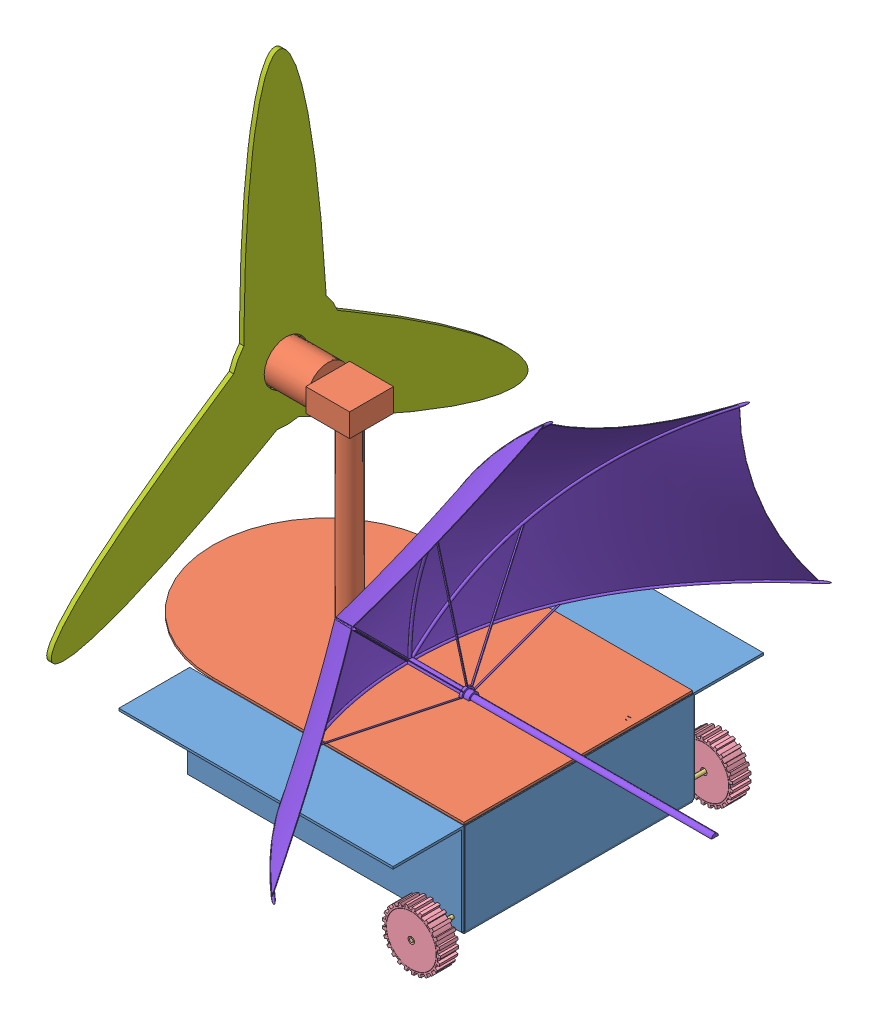
SolidWorks assembly eco_bot, configuration Default. Lengths in mm.
Overall size (551.58 654.61 611.22).
10 component instances, 8 part files, 21 mates.
Components (placement in the parent):
- eco_bot_chasssis-1: eco_bot_chasssis [Default] at (134.5678 118.3464 332.5664) size (301 102.54 405.08)
- eco_bot_upper_cover-1: eco_bot_upper_cover [Default] at (145.8453 220.8864 348.4548) x (0 0 -1) z (1 0 0) size (250 238.55 400)
- shaft_eco-1: shaft_eco [Default] at (286.9011 130.8864 513.8635) x (0 0 -1) z (1 0 0) size (340 4 4)
- wheel_eco-1: wheel_eco [Default] at (286.9011 130.8864 493.8635) x (0.596199 0.802837 0) z (0 0 1) size (63.75 63.63 20)
- wheel_eco-2: wheel_eco [Default] at (286.9011 130.8864 193.8635) x (-0.67562 -0.73725 0) z (0 0 -1) size (63.75 63.63 20)
- wheel_eco-3: wheel_eco [Default] at (44.672 132.8864 320.4458) size (63.75 63.63 20)
- eco_bot_front_shaft-1: eco_bot_front_shaft [Default] at (44.672 132.8864 360.4458) x (1 0 0) z (0 1 0) size (4.04 65.23 42.54)
- Servo motor-1: Servo motor [sin servohorn] at (55.03 216.9264 331.3338) x (-1 0 0) z (0 0 1) size (62.3 43.5 20)
- fin-1: fin [Default] at (-28.4749 436.9378 340.454) x (0 0 -1) z (1 0 0) size (539.16 476.52 33.5)
- umbrella-1: umbrella [Default] at (257.3946 288.3165 342.6703) x (0 -1 0) z (0 0 -1) size (309.59 359.33 611.22)
Mates (geometry in assembly coordinates):
- Coincident1: coincident anti-aligned: plane of eco_bot_chasssis-1 through (134.5678 220.8864 332.5664) normal (0 1 0); plane of eco_bot_upper_cover-1 through (21.3251 220.8864 340.7835) normal (0 -1 0)
- Parallel2: parallel aligned: line of eco_bot_chasssis-1 through (296.9011 220.8864 216.3235) axis (-1 0 0); line of eco_bot_upper_cover-1 through (296.3251 220.8864 215.7835) axis (-1 0 0)
- Distance1: distance = 77 mm: line of eco_bot_upper_cover-1 through (296.3251 220.8864 215.7835) axis (-1 0 0); line of eco_bot_chasssis-1 through (296.9011 220.8864 138.7835) axis (-1 0 0)
- Concentric1: concentric anti-aligned: cylinder of eco_bot_chasssis-1 through (286.9011 130.8864 543.8635) axis (0 0 -1) radius 2; cylinder of shaft_eco-1 through (286.9011 130.8864 173.8635) axis (0 0 1) radius 2
- Distance2: distance = 45 mm aligned: plane of shaft_eco-1 through (286.9011 130.8864 513.8635) normal (0 0 1); plane of eco_bot_chasssis-1 through (-3.0989 220.8864 468.8635) normal (0 0 1)
- Coincident10: coincident aligned: plane of shaft_eco-1 through (286.9011 130.8864 173.8635) normal (0 0 -1); plane of wheel_eco-2 through (286.9011 130.8864 173.8635) normal (0 0 -1)
- Coincident11: coincident aligned: plane of shaft_eco-1 through (286.9011 130.8864 513.8635) normal (0 0 1); plane of wheel_eco-1 through (286.9011 130.8864 513.8635) normal (0 0 1)
- Concentric3: concentric aligned: cylinder of shaft_eco-1 through (286.9011 130.8864 173.8635) axis (0 0 1) radius 2; cylinder of wheel_eco-2 through (286.9011 130.8864 173.8635) axis (0 0 1) radius 3.5
- Coincident12: coincident aligned: plane of shaft_eco-1 through (286.9011 130.8864 173.8635) normal (0 0 -1); plane of wheel_eco-2 through (286.9011 130.8864 173.8635) normal (0 0 -1)
- Coincident13: coincident aligned: plane of shaft_eco-1 through (286.9011 130.8864 513.8635) normal (0 0 1); plane of wheel_eco-1 through (286.9011 130.8864 513.8635) normal (0 0 1)
- Concentric4: concentric anti-aligned: cylinder of shaft_eco-1 through (286.9011 130.8864 173.8635) axis (0 0 1) radius 2; cylinder of wheel_eco-1 through (286.9011 130.8864 513.8635) axis (0 0 -1) radius 3.5
- Concentric5: concentric anti-aligned: cylinder of wheel_eco-3 through (44.672 132.8864 340.4458) axis (0 0 -1) radius 3.5; cylinder of eco_bot_front_shaft-1 through (44.672 132.8864 300.4458) axis (0 0 1) radius 2
- Distance5: distance = 20 mm anti-aligned: plane of wheel_eco-3 through (44.672 132.8864 320.4458) normal (0 0 -1); plane of eco_bot_front_shaft-1 through (44.672 132.8864 300.4458) normal (0 0 1)
- Coincident17: coincident anti-aligned: plane of eco_bot_front_shaft-1 through (44.672 173.4264 360.4458) normal (0 1 0); plane of Servo motor-1 through (44.13 173.4264 331.3338) normal (0 -1 0)
- Distance6: distance = 21.652 mm aligned: plane of Servo motor-1 through (75.03 188.9264 341.3338) normal (0 0 1); plane of eco_bot_front_shaft-1 through (44.672 132.8864 362.9858) normal (0 0 1)
- Distance7: distance = 10 mm anti-aligned: plane of eco_bot_front_shaft-1 through (42.672 130.8864 297.9058) normal (0 -1 0); plane of eco_bot_chasssis-1 through (134.5678 120.8864 332.5664) normal (0 1 0)
- Distance8: distance = 7.62 mm aligned: plane of Servo motor-1 through (35.03 188.9264 321.3338) normal (-1 0 0); plane of eco_bot_front_shaft-1 through (42.65 173.4264 298.0263) normal (-1 0 0)
- Concentric6: concentric aligned: cylinder of eco_bot_upper_cover-1 through (-28.4749 436.9378 340.454) axis (1 0 0) radius 22.5; circle of fin-1
- Coincident18: coincident anti-aligned: plane of eco_bot_upper_cover-1 through (-28.4749 436.9378 340.454) normal (-1 0 0); plane of fin-1 through (-28.4749 436.9378 340.454) normal (1 0 0)
- Coincident19: coincident anti-aligned: plane of eco_bot_upper_cover-1 through (21.3251 223.4264 340.7835) normal (0 1 0); plane of umbrella-1 through (718.5745 223.4264 673.2432) normal (0 -1 0)
- Distance9: distance = 151.5783 mm aligned: plane of umbrella-1 through (447.9034 219.618 190.141) normal (1 0 0); plane of eco_bot_upper_cover-1 through (296.3251 223.4264 215.7835) normal (1 0 0)
